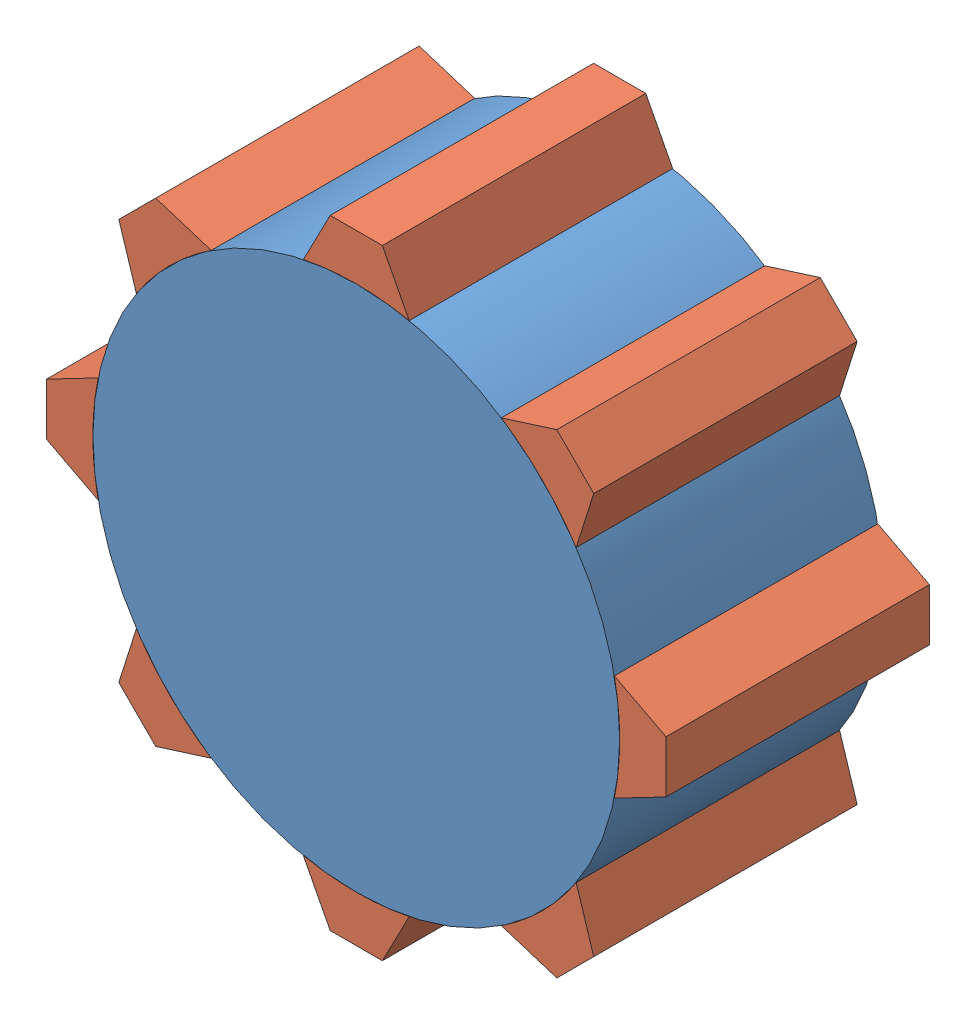
SolidWorks assembly Assem4, configuration Default. Lengths in mm.
Overall size (23.51 23.51 10).
9 component instances, 2 part files, 17 mates.
Components (placement in the parent):
- Part2-2: Part2 [Default] at origin size (20 20 10)
- Part3-1: Part3 [Default] at origin size (4.02 1.96 10)
- Part3-2: Part3 [Default] x (0.707107 -0.707107 0) z (0 0 1) size (4.02 1.96 10)
- Part3-3: Part3 [Default] x (0 -1 0) z (0 0 1) size (4.02 1.96 10)
- Part3-4: Part3 [Default] x (-0.707107 -0.707107 0) z (0 0 1) size (4.02 1.96 10)
- Part3-5: Part3 [Default] x (-1 0 0) z (0 0 1) size (4.02 1.96 10)
- Part3-6: Part3 [Default] x (-0.707107 0.707107 0) z (0 0 1) size (4.02 1.96 10)
- Part3-7: Part3 [Default] x (0 1 0) z (0 0 1) size (4.02 1.96 10)
- Part3-8: Part3 [Default] x (0.707107 0.707107 0) z (0 0 1) size (4.02 1.96 10)
Mates (geometry in assembly coordinates):
- Coincident1: coordinate: point of Part2-2
- Concentric1: concentric aligned: cylinder of Part2-2 through (0 0 10) axis (0 0 -1) radius 10; cylinder of Part3-5 through (0 0 10) axis (0 0 -1) radius 10
- Concentric2: concentric aligned: cylinder of Part2-2 through (0 0 10) axis (0 0 -1) radius 10; cylinder of Part3-8 through (0 0 10) axis (0 0 -1) radius 10
- Concentric3: concentric aligned: cylinder of Part2-2 through (0 0 10) axis (0 0 -1) radius 10; cylinder of Part3-4 through (0 0 10) axis (0 0 -1) radius 10
- Concentric4: concentric aligned: cylinder of Part2-2 through (0 0 10) axis (0 0 -1) radius 10; cylinder of Part3-2 through (0 0 10) axis (0 0 -1) radius 10
- Concentric5: concentric aligned: cylinder of Part2-2 through (0 0 10) axis (0 0 -1) radius 10; cylinder of Part3-3 through (0 0 10) axis (0 0 -1) radius 10
- Concentric6: concentric aligned: cylinder of Part2-2 through (0 0 10) axis (0 0 -1) radius 10; cylinder of Part3-7 through (0 0 10) axis (0 0 -1) radius 10
- Concentric7: concentric aligned: cylinder of Part2-2 through (0 0 10) axis (0 0 -1) radius 10; cylinder of Part3-1 through (0 0 10) axis (0 0 -1) radius 10
- Concentric8: concentric aligned: cylinder of Part2-2 through (0 0 10) axis (0 0 -1) radius 10; cylinder of Part3-6 through (0 0 10) axis (0 0 -1) radius 10
- Coincident3: coincident aligned: plane of Part2-2 through (0 0 10) normal (0 0 1); plane of Part3-8 through (0 0 10) normal (0 0 1)
- Coincident4: coincident aligned: plane of Part2-2 through (0 0 10) normal (0 0 1); plane of Part3-1 through (0 0 10) normal (0 0 1)
- Coincident5: coincident aligned: plane of Part2-2 through (0 0 10) normal (0 0 1); plane of Part3-2 through (0 0 10) normal (0 0 1)
- Coincident6: coincident aligned: plane of Part2-2 through (0 0 10) normal (0 0 1); plane of Part3-3 through (0 0 10) normal (0 0 1)
- Coincident7: coincident aligned: plane of Part2-2 through (0 0 10) normal (0 0 1); plane of Part3-4 through (0 0 10) normal (0 0 1)
- Coincident8: coincident aligned: plane of Part2-2 through (0 0 10) normal (0 0 1); plane of Part3-5 through (0 0 10) normal (0 0 1)
- Coincident9: coincident aligned: plane of Part2-2 through (0 0 10) normal (0 0 1); plane of Part3-7 through (0 0 10) normal (0 0 1)
- Coincident10: coincident aligned: plane of Part2-2 through (0 0 10) normal (0 0 1); plane of Part3-6 through (0 0 10) normal (0 0 1)
